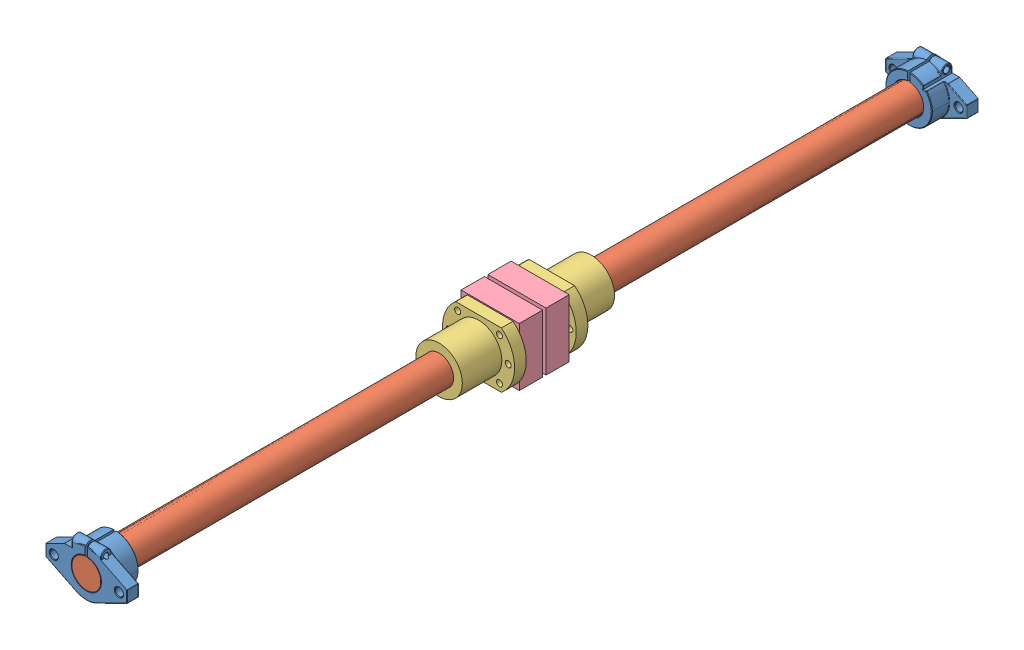
SolidWorks assembly Montagem Guia, configuration Default. Lengths in mm.
Overall size (70 50 732.51).
7 component instances, 4 part files, 17 mates.
Components (placement in the parent):
- Shaft support SHF25-1: Shaft support SHF25 [Default] at (4.0374 -3.5446 -12.9006) size (70 42 25.01)
- guia-1: guia [Default] at (4.0374 -3.5446 -12.9006) x (-0.923728 -0.383049 0) z (-0.383049 0.923728 0) size (25 732.5 25)
- Shaft support SHF25-2: Shaft support SHF25 [Default] at (4.0374 -3.5446 719.5994) x (-1 0 0) z (0 0 -1) size (70 42 25.01)
- LMF25UU-1: LMF25UU [Default] at (4.0374 -3.5446 372.0994) x (0 1 0) z (1 0 0) size (48 44 62)
- LMF25UU-2: LMF25UU [Default] at (4.0374 -3.5446 329.0994) x (0 1 0) z (-1 0 0) size (48 44 62)
- bucha-1: bucha [Default] at (4.0374 -3.5446 372.0994) x (1 0 0) z (0 1 0) size (50 20 50)
- bucha-2: bucha [Default] at (4.0374 -3.5446 349.0994) x (1 0 0) z (0 1 0) size (50 20 50)
Mates (geometry in assembly coordinates):
- Coincident1: coincident aligned: plane of Shaft support SHF25-1 through (4.0374 -3.5446 -12.9006) normal (0 0 -1); plane of guia-1 through (4.0374 -3.5446 -12.9006) normal (0 0 -1)
- Concentric1: concentric aligned: cylinder of Shaft support SHF25-1 through (4.0374 -3.5446 12.0994) axis (0 0 -1) radius 12.5; cylinder of guia-1 through (4.0374 -3.5446 719.5994) axis (0 0 -1) radius 12.5
- Concentric2: concentric anti-aligned: cylinder of guia-1 through (4.0374 -3.5446 719.5994) axis (0 0 -1) radius 12.5; cylinder of Shaft support SHF25-2 through (4.0374 -3.5446 694.5994) axis (0 0 1) radius 12.5
- Coincident2: coincident aligned: plane of guia-1 through (4.0374 -3.5446 719.5994) normal (0 0 1); plane of Shaft support SHF25-2 through (4.0374 -3.5446 719.5994) normal (0 0 1)
- Parallel1: parallel aligned: plane of Shaft support SHF25-1 through (-30.9626 -3.5446 -2.9006) normal (-1 0 0); plane of Shaft support SHF25-2 through (-30.9626 -3.5446 709.5994) normal (-1 0 0)
- Concentric3: concentric anti-aligned: cylinder of guia-1 through (4.0374 -3.5446 719.5994) axis (0 0 -1) radius 12.5; cylinder of LMF25UU-1 through (4.0374 -3.5446 418.5644) axis (0 0 1) radius 12.5
- Concentric4: concentric anti-aligned: cylinder of guia-1 through (4.0374 -3.5446 719.5994) axis (0 0 -1) radius 12.5; cylinder of LMF25UU-2 through (4.0374 -3.5446 331.5654) axis (0 0 1) radius 20
- Distance1: distance = 43 mm anti-aligned: plane of LMF25UU-2 through (4.0374 -3.5446 329.0994) normal (0 0 1); plane of LMF25UU-1 through (4.0374 -3.5446 372.0994) normal (0 0 -1)
- Coincident5: coincident aligned: plane of LMF25UU-1 through (-15.584 20.4554 428.5654) normal (0 1 0); plane of LMF25UU-2 through (23.6588 20.4554 365.5654) normal (0 1 0)
- Perpendicular1: perpendicular: plane of Shaft support SHF25-2 through (39.0374 -3.5446 709.5994) normal (1 0 0); plane of LMF25UU-1 through (-15.584 20.4554 428.5654) normal (0 1 0)
- Concentric5: concentric anti-aligned: cylinder of guia-1 through (4.0374 -3.5446 719.5994) axis (0 0 -1) radius 12.5; cylinder of bucha-1 through (4.0374 -3.5446 398.5654) axis (0 0 1) radius 12.5
- Parallel3: parallel aligned: plane of LMF25UU-1 through (-15.584 -27.5446 428.5654) normal (0 -1 0); plane of bucha-1 through (-20.9626 -28.5446 398.5654) normal (0 -1 0)
- Coincident8: coincident anti-aligned: plane of LMF25UU-1 through (4.0374 -3.5446 418.5654) normal (0 0 -1); plane of bucha-1 through (4.0374 -3.5446 418.5654) normal (0 0 1)
- Concentric6: concentric anti-aligned: cylinder of guia-1 through (4.0374 -3.5446 719.5994) axis (0 0 -1) radius 12.5; cylinder of bucha-2 through (4.0374 -3.5446 375.5654) axis (0 0 1) radius 12.5
- Coincident9: coincident anti-aligned: plane of LMF25UU-2 through (4.0374 -3.5446 375.5654) normal (0 0 1); plane of bucha-2 through (4.0374 -3.5446 375.5654) normal (0 0 -1)
- Coincident10: coincident aligned: plane of bucha-1 through (29.0374 21.4554 398.5654) normal (1 0 0); plane of bucha-2 through (29.0374 21.4554 375.5654) normal (1 0 0)
- Distance2: distance = 337 mm aligned: plane of bucha-2 through (4.0374 -3.5446 349.0994) normal (0 0 1); plane of Shaft support SHF25-1 through (4.0374 -3.5446 12.0994) normal (0 0 1)
